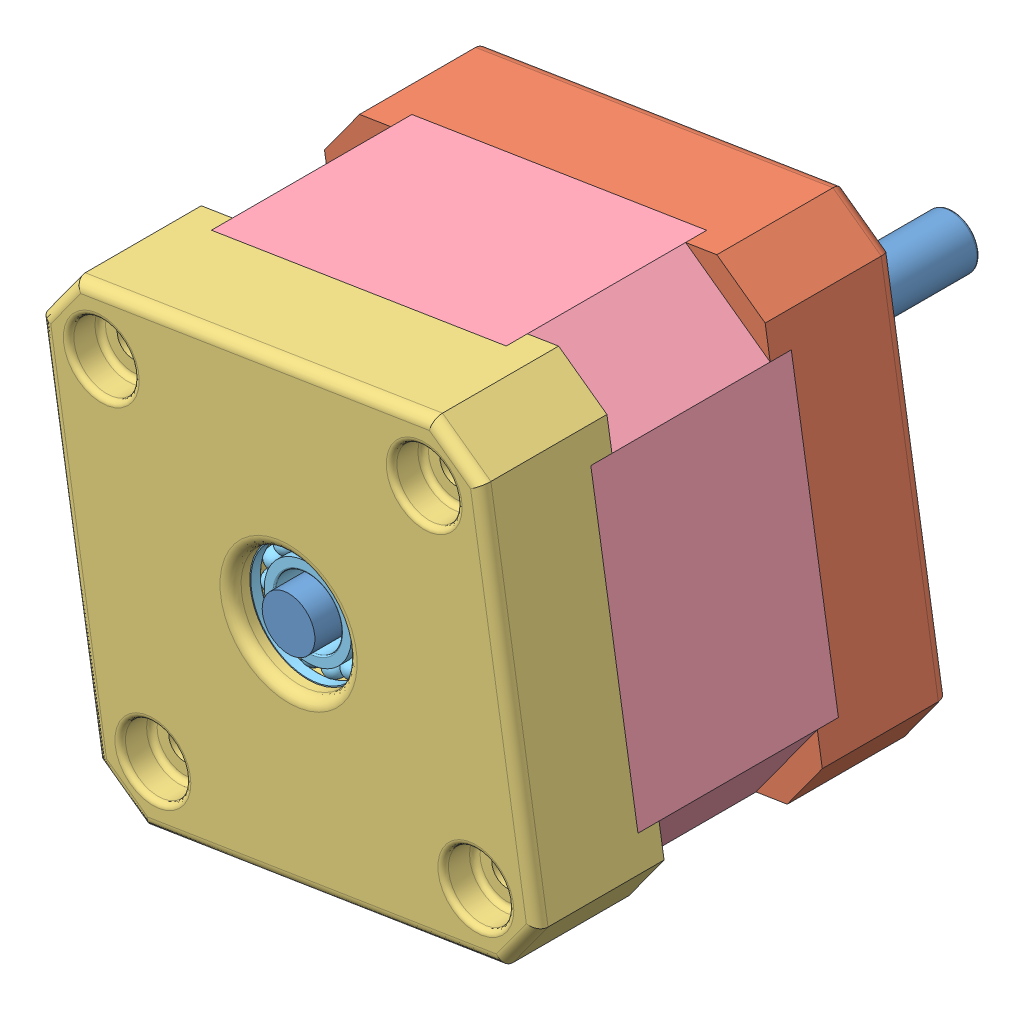
SolidWorks assembly EI_Nema17, configuration Default. Lengths in mm.
Overall size (48.45 48.45 63).
6 component instances, 5 part files, 12 mates.
Components (placement in the parent):
- Axial rod 1-1: Axial rod 1 [Default] at (-58.2353 9.2851 106.3831) x (0.407635 0.913145 0) z (0 0 -1) size (5 5 63)
- Back plate 1-1: Back plate 1 [Default] at (-58.2353 9.2851 67.3831) x (-0.157849 0.987463 0) z (0 0 1) size (42.3 42.3 14)
- Base 1-1: Base 1 [Default] at (-58.2353 9.2851 106.3831) x (-0.157849 0.987463 0) z (0 0 -1) size (42.3 42.3 12)
- Body 1-1: Body 1 [Default] at (-58.2353 9.2851 77.3831) x (-0.157849 0.987463 0) z (0 0 1) size (42.3 42.3 19)
- instrument ball bearing_68_am-1: instrument ball bearing_68_am [PreviewCfg] at (-58.2353 9.2851 102.9706) x (0 0 -1) z (1 0 0) size (3.17 12.7 12.7)
- instrument ball bearing_68_am-2: instrument ball bearing_68_am [PreviewCfg] at (-58.2353 9.2851 70.7956) x (0 0 -1) z (1 0 0) size (3.17 12.7 12.7)
Mates (geometry in assembly coordinates):
- Coincident1: coincident anti-aligned: plane of Back plate 1-1 through (-58.2353 9.2851 77.3831) normal (0 0 1); plane of Body 1-1 through (-58.2353 9.2851 77.3831) normal (0 0 -1)
- Coincident2: coincident aligned: plane of Back plate 1-1 through (-76.4131 -10.9884 79.3831) normal (-0.987463 -0.157849 0); plane of Body 1-1 through (-76.8866 -8.026 96.3831) normal (-0.987463 -0.157849 0)
- Coincident3: coincident aligned: plane of Back plate 1-1 through (-37.9618 -8.8926 79.3831) normal (0.157849 -0.987463 0); plane of Body 1-1 through (-40.9242 -9.3662 96.3831) normal (0.157849 -0.987463 0)
- Coincident4: coincident aligned: plane of Base 1-1 through (-76.4131 -10.9884 94.3831) normal (-0.987463 -0.157849 0); plane of Body 1-1 through (-76.8866 -8.026 96.3831) normal (-0.987463 -0.157849 0)
- Coincident5: coincident anti-aligned: plane of Base 1-1 through (-58.2353 9.2851 96.3831) normal (0 0 -1); plane of Body 1-1 through (-58.2353 9.2851 96.3831) normal (0 0 1)
- Coincident6: coincident aligned: plane of Base 1-1 through (-71.8318 -14.3069 94.3831) normal (0.157849 -0.987463 0); plane of Body 1-1 through (-40.9242 -9.3662 96.3831) normal (0.157849 -0.987463 0)
- Concentric1: concentric anti-aligned: cylinder of Axial rod 1-1 through (-58.2353 9.2851 43.3831) axis (0 0 1) radius 2.5; cylinder of Back plate 1-1 through (-58.2353 9.2851 79.3831) axis (0 0 -1) radius 2.5
- Coincident7: coincident aligned: plane of Axial rod 1-1 through (-58.2353 9.2851 106.3831) normal (0 0 1); plane of Base 1-1 through (-58.2353 9.2851 106.3831) normal (0 0 1)
- Concentric3: concentric anti-aligned: cylinder of Axial rod 1-1 through (-58.2353 9.2851 43.3831) axis (0 0 1) radius 2.5; cylinder of instrument ball bearing_68_am-2 through (-58.2353 9.2851 91.4331) axis (0 0 -1) radius 3.175
- Coincident8: coincident aligned: plane of Back plate 1-1 through (-58.2353 9.2851 72.3831) normal (0 0 -1); circle of instrument ball bearing_68_am-2
- Concentric4: concentric anti-aligned: cylinder of Axial rod 1-1 through (-58.2353 9.2851 43.3831) axis (0 0 1) radius 2.5; cylinder of instrument ball bearing_68_am-1 through (-58.2353 9.2851 123.6081) axis (0 0 -1) radius 3.175
- Coincident9: coincident anti-aligned: plane of Base 1-1 through (-58.2353 9.2851 101.3831) normal (0 0 1); circle of instrument ball bearing_68_am-1
